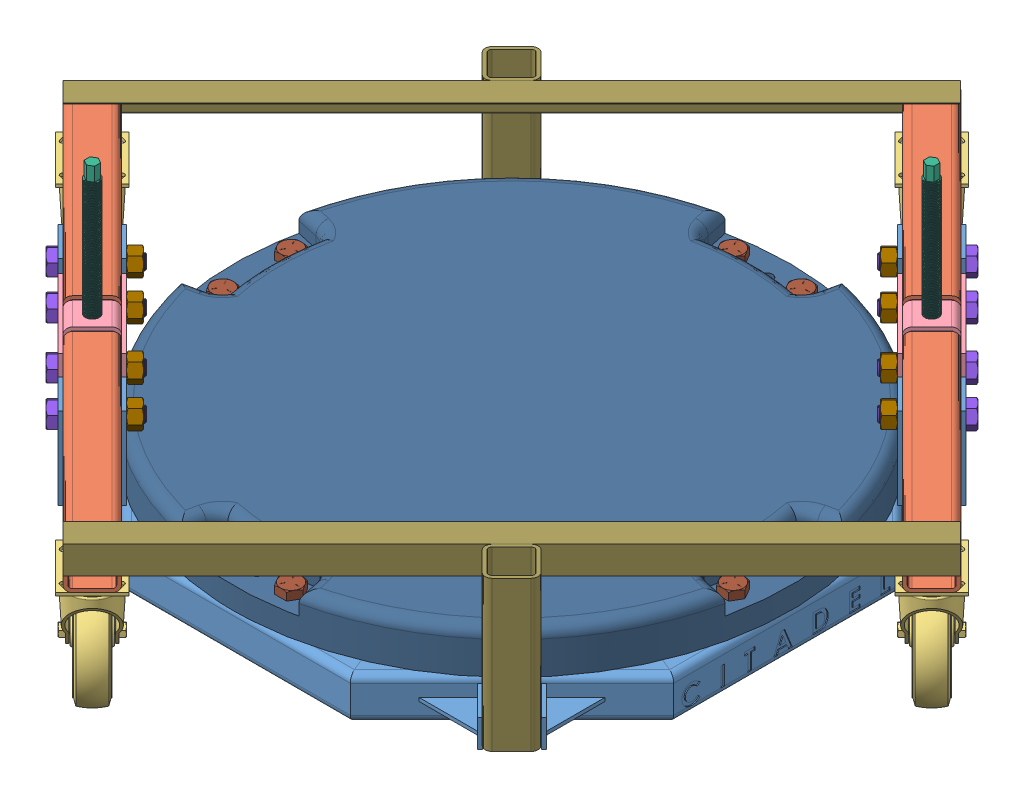
SolidWorks assembly Hex Base Tubing Assembly2 screw, configuration Default. Lengths in mm.
Overall size (1664.24 559.66 1664.24).
54 component instances, 12 part files, 81 mates.
Components (placement in the parent):
- Hex Base Box Tubing-1: Hex Base Box Tubing [Default<As Machined>] at (554.5207 455.268 811.2927) x (0 0 -1) z (0 1 0) size (1171.84 1171.84 285.75)
- Tube Arm-1: Tube Arm [Default<As Machined>] at (910.3441 671.4952 398.9153) x (-0.707105 -0.002496 -0.707105) z (-0.707107 0 0.707107) size (476.53 76.2 76.2)
- Tube Arm-2: Tube Arm [Default<As Machined>] at (966.8981 671.4952 455.4693) x (0.707105 -0.002496 0.707105) z (-0.707107 0 0.707107) size (476.53 76.2 76.2)
- Tube Arm-3: Tube Arm [Default<As Machined>] at (142.1433 671.4952 1167.1161) x (-0.707105 -0.002496 -0.707105) z (-0.707107 0 0.707107) size (476.53 76.2 76.2)
- Tube Arm-4: Tube Arm [Default<As Machined>] at (198.6973 671.4952 1223.6701) x (0.707105 -0.002496 0.707105) z (-0.707107 0 0.707107) size (476.53 76.2 76.2)
- 2498T660_EASY-TURN NSF-CERTIFIED CASTER-1: 2498T660_EASY-TURN NSF-CERTIFIED CASTER [2498T66] at (614.9884 632.3527 103.5596) x (-0.707105 -0.002496 -0.707105) z (0.707107 0 -0.707107) size (215.9 241.3 95.25)
- 2498T660_EASY-TURN NSF-CERTIFIED CASTER-2: 2498T660_EASY-TURN NSF-CERTIFIED CASTER [2498T66] at (1262.2538 632.3527 750.825) x (0.707105 -0.002496 0.707105) z (-0.707107 0 0.707107) size (215.9 241.3 95.25)
- 2498T660_EASY-TURN NSF-CERTIFIED CASTER-3: 2498T660_EASY-TURN NSF-CERTIFIED CASTER [2498T66] at (-153.2124 632.3527 871.7604) x (-0.707105 -0.002496 -0.707105) z (0.707107 0 -0.707107) size (215.9 241.3 95.25)
- 2498T660_EASY-TURN NSF-CERTIFIED CASTER-4: 2498T660_EASY-TURN NSF-CERTIFIED CASTER [2498T66] at (494.053 632.3527 1519.0258) x (0.707105 -0.002496 0.707105) z (-0.707107 0 0.707107) size (215.9 241.3 95.25)
- Coupler-2 Assembly-1: Coupler-2 Assembly [Default] at (973.9039 570.6335 267.0357) x (0.707107 0 0.707107) z (-0.707107 0 0.707107) size (180 101.54 88.9)
  - Center Tube Coupler-2-1: Center Tube Coupler-2 [Default<As Machined>] at (58.2991 100.7931 138.1965) size (180 76.2 88.9)
  - 94815A118_RIGHT-HAND GENERAL PURPOSE ACME HEX NUT-2: 94815A118_RIGHT-HAND GENERAL PURPOSE ACME HEX NUT [94815A118] at (88.2991 50.1915 138.1965) x (-0.537908 0 -0.843004) z (0 1 0) size (41.27 52.42 25.67)
  - 94815A118_RIGHT-HAND GENERAL PURPOSE ACME HEX NUT-3: 94815A118_RIGHT-HAND GENERAL PURPOSE ACME HEX NUT [94815A118] at (88.2991 120.0415 138.1965) x (1 0 0) z (0 1 0) size (41.27 52.42 25.67)
- 98935A754_ASTM A108 STEEL ACME LEAD SCREW-18 inch-1: 98935A754_ASTM A108 STEEL ACME LEAD SCREW-18 inch [98935A754] at (938.6211 721.968 427.1923) x (1 0 0) z (0 1 0) size (29.33 26.07 459.74)
- Coupler-2 Assembly-2: Coupler-2 Assembly [Default] at (205.7031 570.6335 1035.2365) x (0.707107 0 0.707107) z (-0.707107 0 0.707107) size (180 101.54 88.9)
  - Center Tube Coupler-2-1: Center Tube Coupler-2 [Default<As Machined>] at (58.2991 100.7931 138.1965) size (180 76.2 88.9)
  - 94815A118_RIGHT-HAND GENERAL PURPOSE ACME HEX NUT-2: 94815A118_RIGHT-HAND GENERAL PURPOSE ACME HEX NUT [94815A118] at (88.2991 50.1915 138.1965) x (-0.537908 0 -0.843004) z (0 1 0) size (41.27 52.42 25.67)
  - 94815A118_RIGHT-HAND GENERAL PURPOSE ACME HEX NUT-3: 94815A118_RIGHT-HAND GENERAL PURPOSE ACME HEX NUT [94815A118] at (88.2991 120.0415 138.1965) x (1 0 0) z (0 1 0) size (41.27 52.42 25.67)
- 98935A754_ASTM A108 STEEL ACME LEAD SCREW-18 inch-2: 98935A754_ASTM A108 STEEL ACME LEAD SCREW-18 inch [98935A754] at (170.4203 721.968 1195.3931) x (1 0 0) z (0 1 0) size (29.33 26.07 459.74)
- Weld in Bung1-8-1: Weld in Bung1-8 [95462A548] at (617.0207 455.268 344.2927) x (-0.837169 0 -0.546944) z (0 1 0) size (31.75 31.75 92.63)
- Weld in Bung1-8-2: Weld in Bung1-8 [95462A548] at (492.0207 455.268 344.2927) x (-0.837169 0 -0.546944) z (0 1 0) size (31.75 31.75 92.63)
- Weld in Bung1-8-3: Weld in Bung1-8 [95462A548] at (617.0207 455.268 1278.2927) x (-0.837169 0 -0.546944) z (0 1 0) size (31.75 31.75 92.63)
- Weld in Bung1-8-4: Weld in Bung1-8 [95462A548] at (87.5207 455.268 748.7927) x (-0.837169 0 -0.546944) z (0 1 0) size (31.75 31.75 92.63)
- Weld in Bung1-8-5: Weld in Bung1-8 [95462A548] at (1021.5207 455.268 873.7927) x (-0.837169 0 -0.546944) z (0 1 0) size (31.75 31.75 92.63)
- Weld in Bung1-8-6: Weld in Bung1-8 [95462A548] at (87.5207 455.268 873.7927) x (-0.837169 0 -0.546944) z (0 1 0) size (31.75 31.75 92.63)
- Weld in Bung1-8-7: Weld in Bung1-8 [95462A548] at (1021.5207 455.268 748.7927) x (-0.837169 0 -0.546944) z (0 1 0) size (31.75 31.75 92.63)
- Weld in Bung1-8-8: Weld in Bung1-8 [95462A548] at (492.0207 455.268 1278.2927) x (-0.837169 0 -0.546944) z (0 1 0) size (31.75 31.75 92.63)
- 91247A922_MEDIUM-STRG GRADE 5 ZINC-PLTD STL CAP SCREW-1: 91247A922_MEDIUM-STRG GRADE 5 ZINC-PLTD STL CAP SCREW [91247A922] at (221.6579 671.4266 1239.6149) x (0.707107 0 -0.707107) z (0.707107 0 0.707107) size (131 43.99 38.1)
- 91247A922_MEDIUM-STRG GRADE 5 ZINC-PLTD STL CAP SCREW-2: 91247A922_MEDIUM-STRG GRADE 5 ZINC-PLTD STL CAP SCREW [91247A922] at (126.1985 671.4266 1144.1555) x (0.707107 0 -0.707107) z (0.707107 0 0.707107) size (131 43.99 38.1)
- 91247A922_MEDIUM-STRG GRADE 5 ZINC-PLTD STL CAP SCREW-3: 91247A922_MEDIUM-STRG GRADE 5 ZINC-PLTD STL CAP SCREW [91247A922] at (52.9286 671.168 1070.8856) x (0.707107 0 -0.707107) z (0.707107 0 0.707107) size (131 43.99 38.1)
- 91247A922_MEDIUM-STRG GRADE 5 ZINC-PLTD STL CAP SCREW-4: 91247A922_MEDIUM-STRG GRADE 5 ZINC-PLTD STL CAP SCREW [91247A922] at (294.9278 671.168 1312.8848) x (0.707107 0 -0.707107) z (0.707107 0 0.707107) size (131 43.99 38.1)
- 91247A922_MEDIUM-STRG GRADE 5 ZINC-PLTD STL CAP SCREW-5: 91247A922_MEDIUM-STRG GRADE 5 ZINC-PLTD STL CAP SCREW [91247A922] at (887.3835 671.4266 382.9705) x (-0.707107 0 0.707107) z (-0.643511 -0.414472 -0.643511) size (131 43.99 38.1)
- 91247A922_MEDIUM-STRG GRADE 5 ZINC-PLTD STL CAP SCREW-6: 91247A922_MEDIUM-STRG GRADE 5 ZINC-PLTD STL CAP SCREW [91247A922] at (1056.1128 671.168 551.6998) x (-0.707107 0 0.707107) z (-0.643511 -0.414472 -0.643511) size (131 43.99 38.1)
- 91247A922_MEDIUM-STRG GRADE 5 ZINC-PLTD STL CAP SCREW-7: 91247A922_MEDIUM-STRG GRADE 5 ZINC-PLTD STL CAP SCREW [91247A922] at (814.1136 671.168 309.7006) x (-0.707107 0 0.707107) z (-0.643511 -0.414472 -0.643511) size (131 43.99 38.1)
- 91247A922_MEDIUM-STRG GRADE 5 ZINC-PLTD STL CAP SCREW-8: 91247A922_MEDIUM-STRG GRADE 5 ZINC-PLTD STL CAP SCREW [91247A922] at (982.8429 671.4266 478.4299) x (-0.707107 0 0.707107) z (-0.643511 -0.414472 -0.643511) size (131 43.99 38.1)
- 95462A548_GRADE 5 STEEL HEX NUT-1: 95462A548_GRADE 5 STEEL HEX NUT [95462A548] at (778.4732 671.168 345.341) x (0.707107 0 0.707107) z (-0.707107 0 0.707107) size (38.1 43.99 27.38)
- 95462A548_GRADE 5 STEEL HEX NUT-2: 95462A548_GRADE 5 STEEL HEX NUT [95462A548] at (947.2025 671.4266 514.0703) x (0.707107 0 0.707107) z (-0.707107 0 0.707107) size (38.1 43.99 27.38)
- 95462A548_GRADE 5 STEEL HEX NUT-3: 95462A548_GRADE 5 STEEL HEX NUT [95462A548] at (1020.4724 671.168 587.3402) x (0.707107 0 0.707107) z (-0.707107 0 0.707107) size (38.1 43.99 27.38)
- 95462A548_GRADE 5 STEEL HEX NUT-4: 95462A548_GRADE 5 STEEL HEX NUT [95462A548] at (851.7431 671.4266 418.6109) x (0.707107 0 0.707107) z (-0.707107 0 0.707107) size (38.1 43.99 27.38)
- 95462A548_GRADE 5 STEEL HEX NUT-5: 95462A548_GRADE 5 STEEL HEX NUT [95462A548] at (88.569 671.168 1035.2452) x (-0.643511 -0.414472 -0.643511) z (0.707107 0 -0.707107) size (38.1 43.99 27.38)
- 95462A548_GRADE 5 STEEL HEX NUT-6: 95462A548_GRADE 5 STEEL HEX NUT [95462A548] at (257.2983 671.4266 1203.9745) x (-0.643511 -0.414472 -0.643511) z (0.707107 0 -0.707107) size (38.1 43.99 27.38)
- 95462A548_GRADE 5 STEEL HEX NUT-7: 95462A548_GRADE 5 STEEL HEX NUT [95462A548] at (161.8389 671.4266 1108.5151) x (-0.643511 -0.414472 -0.643511) z (0.707107 0 -0.707107) size (38.1 43.99 27.38)
- 95462A548_GRADE 5 STEEL HEX NUT-8: 95462A548_GRADE 5 STEEL HEX NUT [95462A548] at (330.5682 671.168 1277.2444) x (-0.643511 -0.414472 -0.643511) z (0.707107 0 -0.707107) size (38.1 43.99 27.38)
- Kuka Base-1: Kuka Base [Default] at (554.5207 493.368 811.2927) x (0 0 1) z (0 1 0) size (1020 1020 81.77)
- 92865A914_MEDIUM-STRG GRADE 5 ZINC-PLTD STL CAP SCREW-3: 92865A914_MEDIUM-STRG GRADE 5 ZINC-PLTD STL CAP SCREW [92865A914] at (492.0207 509.357 1278.2927) x (0 -1 0) z (0 0 1) size (80.56 43.99 38.1)
- 92865A914_MEDIUM-STRG GRADE 5 ZINC-PLTD STL CAP SCREW-4: 92865A914_MEDIUM-STRG GRADE 5 ZINC-PLTD STL CAP SCREW [92865A914] at (87.5207 509.357 873.7927) x (0 -1 0) z (0 0 1) size (80.56 43.99 38.1)
- 92865A914_MEDIUM-STRG GRADE 5 ZINC-PLTD STL CAP SCREW-5: 92865A914_MEDIUM-STRG GRADE 5 ZINC-PLTD STL CAP SCREW [92865A914] at (492.0207 509.357 344.2927) x (0 -1 0) z (0 0 1) size (80.56 43.99 38.1)
- 92865A914_MEDIUM-STRG GRADE 5 ZINC-PLTD STL CAP SCREW-6: 92865A914_MEDIUM-STRG GRADE 5 ZINC-PLTD STL CAP SCREW [92865A914] at (617.0207 509.357 1278.2927) x (0 -1 0) z (0 0 1) size (80.56 43.99 38.1)
- 92865A914_MEDIUM-STRG GRADE 5 ZINC-PLTD STL CAP SCREW-7: 92865A914_MEDIUM-STRG GRADE 5 ZINC-PLTD STL CAP SCREW [92865A914] at (617.0207 509.357 344.2927) x (0 -1 0) z (0 0 1) size (80.56 43.99 38.1)
- 92865A914_MEDIUM-STRG GRADE 5 ZINC-PLTD STL CAP SCREW-8: 92865A914_MEDIUM-STRG GRADE 5 ZINC-PLTD STL CAP SCREW [92865A914] at (1021.5207 509.357 873.7927) x (0 -1 0) z (0 0 1) size (80.56 43.99 38.1)
- 92865A914_MEDIUM-STRG GRADE 5 ZINC-PLTD STL CAP SCREW-9: 92865A914_MEDIUM-STRG GRADE 5 ZINC-PLTD STL CAP SCREW [92865A914] at (87.5207 509.357 748.7927) x (0 -1 0) z (0 0 1) size (80.56 43.99 38.1)
- 92865A914_MEDIUM-STRG GRADE 5 ZINC-PLTD STL CAP SCREW-10: 92865A914_MEDIUM-STRG GRADE 5 ZINC-PLTD STL CAP SCREW [92865A914] at (1021.5207 509.357 748.7927) x (0 -1 0) z (0 0 1) size (80.56 43.99 38.1)
- Angle Cross Brace-1: Angle Cross Brace [Default<As Machined>] at (-224.0719 711.5729 854.7825) x (0.707107 0 -0.707107) z (0.001765 -0.999997 0.001765) size (1161.6 127 275)
- Angle Cross Brace-2: Angle Cross Brace [Default<As Machined>] at (1332.4062 711.5729 768.51) x (-0.707107 0 0.707107) z (-0.001765 -0.999997 -0.001765) size (1161.6 127 275)
Mates (geometry in assembly coordinates):
- Coincident1: coincident: cylinder of Hex Base Box Tubing-1 through (849.0524 671.168 274.7618) axis (-0.707107 0 0.707107) radius 12.7; circle of Tube Arm-1
- Coincident2: coincident: plane of Hex Base Box Tubing-1 through (965.5619 455.268 400.2515) normal (-0.707107 0 0.707107); plane of Tube Arm-1 through (600.2835 695.7059 34.9732) normal (0.707107 0 -0.707107)
- Concentric1: concentric: cylinder of Hex Base Box Tubing-1 through (1091.0516 671.168 516.761) axis (-0.707107 0 0.707107) radius 12.7; cylinder of Tube Arm-2 through (1086.5615 671.168 521.2511) axis (-0.707107 0 0.707107) radius 12.7
- Coincident3: coincident: plane of Hex Base Box Tubing-1 through (965.5619 455.268 400.2515) normal (-0.707107 0 0.707107); plane of Tube Arm-2 through (1330.7506 644.9061 765.4402) normal (0.707107 0 -0.707107)
- Concentric6: concentric: cylinder of Hex Base Box Tubing-1 through (322.8508 671.168 1284.9618) axis (-0.707107 0 0.707107) radius 12.7; cylinder of Tube Arm-4 through (318.3607 671.168 1289.4519) axis (-0.707107 0 0.707107) radius 12.7
- Coincident7: coincident: plane of Hex Base Box Tubing-1 through (143.4795 455.268 1222.3339) normal (0.707107 0 -0.707107); plane of Tube Arm-4 through (508.7579 695.7059 1587.6122) normal (-0.707107 0 0.707107)
- Concentric7: concentric: cylinder of Hex Base Box Tubing-1 through (17.9898 671.168 1105.8244) axis (0.707107 0 -0.707107) radius 12.7; cylinder of Tube Arm-3 through (76.3615 671.168 1047.4527) axis (-0.707107 0 0.707107) radius 12.7
- Coincident8: coincident: plane of Hex Base Box Tubing-1 through (197.3611 455.268 1168.4523) normal (-0.707107 0 0.707107); plane of Tube Arm-3 through (-167.9173 695.7059 803.174) normal (0.707107 0 -0.707107)
- Coincident14: coincident: plane of Tube Arm-1 through (555.4943 632.2061 79.9865) normal (0.001765 -0.999997 0.001765); plane of 2498T660_EASY-TURN NSF-CERTIFIED CASTER-1 through (690.1979 632.4993 111.4172) normal (-0.001765 0.999997 -0.001765)
- Coincident15: coincident: plane of Tube Arm-1 through (555.4719 644.9061 79.9641) normal (-0.707105 -0.002496 -0.707105); plane of 2498T660_EASY-TURN NSF-CERTIFIED CASTER-1 through (539.7887 626.6499 95.7118) normal (-0.707105 -0.002496 -0.707105)
- Distance1: distance = 9.525 mm: plane of 2498T660_EASY-TURN NSF-CERTIFIED CASTER-1 through (690.2077 626.9431 111.427) normal (0.707107 0 -0.707107); plane of Tube Arm-1 through (600.2835 695.7059 34.9732) normal (0.707107 0 -0.707107)
- Coincident18: coincident: plane of Tube Arm-2 through (1321.7479 632.2061 774.3981) normal (-0.001765 -0.999997 -0.001765); plane of 2498T660_EASY-TURN NSF-CERTIFIED CASTER-2 through (1187.0443 632.4993 742.9674) normal (0.001765 0.999997 0.001765)
- Coincident20: coincident: plane of Tube Arm-2 through (1285.9389 695.7059 810.4311) normal (0.707105 -0.002496 0.707105); plane of 2498T660_EASY-TURN NSF-CERTIFIED CASTER-2 through (1337.4536 626.6499 758.6728) normal (0.707105 -0.002496 0.707105)
- Distance2: distance = 9.525 mm: plane of Tube Arm-2 through (1330.7506 644.9061 765.4402) normal (0.707107 0 -0.707107); plane of 2498T660_EASY-TURN NSF-CERTIFIED CASTER-2 through (1254.3864 626.9431 675.6057) normal (0.707107 0 -0.707107)
- Coincident22: coincident: plane of Tube Arm-3 through (-212.7065 632.2061 848.1873) normal (0.001765 -0.999997 0.001765); plane of 2498T660_EASY-TURN NSF-CERTIFIED CASTER-3 through (-78.0029 632.4993 879.618) normal (-0.001765 0.999997 -0.001765)
- Coincident23: coincident: plane of Tube Arm-3 through (-212.7289 644.9061 848.1649) normal (-0.707105 -0.002496 -0.707105); plane of 2498T660_EASY-TURN NSF-CERTIFIED CASTER-3 through (-228.4121 626.6499 863.9126) normal (-0.707105 -0.002496 -0.707105)
- Distance3: distance = 9.525 mm: plane of Tube Arm-3 through (-167.9173 695.7059 803.174) normal (0.707107 0 -0.707107); plane of 2498T660_EASY-TURN NSF-CERTIFIED CASTER-3 through (-77.9931 626.9431 879.6278) normal (0.707107 0 -0.707107)
- Coincident25: coincident: plane of Tube Arm-4 through (553.5471 632.2061 1542.5989) normal (-0.001765 -0.999997 -0.001765); plane of 2498T660_EASY-TURN NSF-CERTIFIED CASTER-4 through (418.8435 632.4993 1511.1682) normal (0.001765 0.999997 0.001765)
- Coincident26: coincident: plane of Tube Arm-4 through (517.7381 695.7059 1578.632) normal (0.707105 -0.002496 0.707105); plane of 2498T660_EASY-TURN NSF-CERTIFIED CASTER-4 through (569.2527 626.6499 1526.8736) normal (0.707105 -0.002496 0.707105)
- Distance4: distance = 9.525 mm: plane of Tube Arm-4 through (562.5498 644.9061 1533.641) normal (0.707107 0 -0.707107); plane of 2498T660_EASY-TURN NSF-CERTIFIED CASTER-4 through (486.1856 626.9431 1443.8065) normal (0.707107 0 -0.707107)
- Slot1: slot: cylinder of Tube Arm-1 through (911.7231 671.405 346.4127) axis (-0.707107 0 0.707107) radius 12.7; cylinder of Coupler-2 Assembly-1/Center Tube Coupler-2-1 through (922.3223 671.4266 348.0317) axis (-0.707107 0 0.707107) radius 12.7; cylinder of Tube Arm-1 through (924.1681 671.4489 358.8578) axis (-0.707107 0 0.707107) radius 12.7
- Slot2: slot: cylinder of Tube Arm-2 through (1019.4007 671.405 454.0903) axis (-0.707107 0 0.707107) radius 12.7; cylinder of Coupler-2 Assembly-1/Center Tube Coupler-2-1 through (1017.7817 671.4266 443.4911) axis (-0.707107 0 0.707107) radius 12.7; cylinder of Tube Arm-2 through (1006.9556 671.4489 441.6453) axis (-0.707107 0 0.707107) radius 12.7
- Coincident70: coincident: plane of Tube Arm-2 through (1330.7506 644.9061 765.4402) normal (0.707107 0 -0.707107); plane of Coupler-2 Assembly-1/Center Tube Coupler-2-1 through (944.3487 671.4266 379.0383) normal (-0.707107 0 0.707107)
- Concentric8: concentric: circle of Coupler-2 Assembly-1/Center Tube Coupler-2-1; circle of 98935A754_ASTM A108 STEEL ACME LEAD SCREW-18 inch-1
- Concentric9: concentric: circle of Hex Base Box Tubing-1; circle of 98935A754_ASTM A108 STEEL ACME LEAD SCREW-18 inch-1
- Coincident71: coincident: plane of Hex Base Box Tubing-1 through (1050.6405 493.368 503.2906) normal (0 1 0); plane of 98935A754_ASTM A108 STEEL ACME LEAD SCREW-18 inch-1 through (938.6211 493.368 427.1923) normal (0 -1 0)
- Slot3: slot: cylinder of Tube Arm-3 through (143.5223 671.405 1114.6135) axis (-0.707107 0 0.707107) radius 12.7; cylinder of Coupler-2 Assembly-2/Center Tube Coupler-2-1 through (91.2597 671.4266 1179.0943) axis (0.707107 0 -0.707107) radius 12.7; cylinder of Tube Arm-3 through (155.9673 671.4489 1127.0586) axis (-0.707107 0 0.707107) radius 12.7
- Slot4: slot: cylinder of Tube Arm-4 through (251.1999 671.405 1222.2911) axis (-0.707107 0 0.707107) radius 12.7; cylinder of Coupler-2 Assembly-2/Center Tube Coupler-2-1 through (186.7191 671.4266 1274.5537) axis (0.707107 0 -0.707107) radius 12.7; cylinder of Tube Arm-4 through (238.7548 671.4489 1209.8461) axis (-0.707107 0 0.707107) radius 12.7
- Coincident72: coincident: plane of Tube Arm-4 through (508.7579 695.7059 1587.6122) normal (-0.707107 0 0.707107); plane of Coupler-2 Assembly-2/Center Tube Coupler-2-1 through (122.2663 671.4266 1201.1207) normal (0.707107 0 -0.707107)
- Concentric10: concentric: circle of Coupler-2 Assembly-2/Center Tube Coupler-2-1; circle of 98935A754_ASTM A108 STEEL ACME LEAD SCREW-18 inch-2
- Concentric11: concentric: circle of Hex Base Box Tubing-1; circle of 98935A754_ASTM A108 STEEL ACME LEAD SCREW-18 inch-2
- Coincident73: coincident: plane of Hex Base Box Tubing-1 through (58.401 493.368 1119.2948) normal (0 1 0); plane of 98935A754_ASTM A108 STEEL ACME LEAD SCREW-18 inch-2 through (170.4203 493.368 1195.3931) normal (0 -1 0)
- Coincident74: coincident: circle of Hex Base Box Tubing-1; circle of Weld in Bung1-8-1
- Coincident75: coincident: circle of Hex Base Box Tubing-1; circle of Weld in Bung1-8-2
- Coincident76: coincident: circle of Hex Base Box Tubing-1; circle of Weld in Bung1-8-7
- Coincident77: coincident: circle of Hex Base Box Tubing-1; circle of Weld in Bung1-8-5
- Coincident78: coincident: circle of Hex Base Box Tubing-1; circle of Weld in Bung1-8-4
- Coincident79: coincident: circle of Hex Base Box Tubing-1; circle of Weld in Bung1-8-6
- Coincident80: coincident: circle of Hex Base Box Tubing-1; circle of Weld in Bung1-8-3
- Coincident81: coincident: circle of Hex Base Box Tubing-1; circle of Weld in Bung1-8-8
- Coincident82: coincident: circle of Coupler-2 Assembly-2/Center Tube Coupler-2-1; circle of 91247A922_MEDIUM-STRG GRADE 5 ZINC-PLTD STL CAP SCREW-1
- Coincident83: coincident: circle of Hex Base Box Tubing-1; circle of 91247A922_MEDIUM-STRG GRADE 5 ZINC-PLTD STL CAP SCREW-4
- Coincident84: coincident: circle of Coupler-2 Assembly-2/Center Tube Coupler-2-1; circle of 91247A922_MEDIUM-STRG GRADE 5 ZINC-PLTD STL CAP SCREW-2
- Coincident85: coincident: circle of Hex Base Box Tubing-1; circle of 91247A922_MEDIUM-STRG GRADE 5 ZINC-PLTD STL CAP SCREW-3
- Coincident86: coincident: circle of Hex Base Box Tubing-1; circle of 91247A922_MEDIUM-STRG GRADE 5 ZINC-PLTD STL CAP SCREW-7
- Coincident87: coincident: circle of Coupler-2 Assembly-1/Center Tube Coupler-2-1; circle of 91247A922_MEDIUM-STRG GRADE 5 ZINC-PLTD STL CAP SCREW-5
- Coincident88: coincident: circle of Coupler-2 Assembly-1/Center Tube Coupler-2-1; circle of 91247A922_MEDIUM-STRG GRADE 5 ZINC-PLTD STL CAP SCREW-8
- Coincident89: coincident: circle of Hex Base Box Tubing-1; circle of 91247A922_MEDIUM-STRG GRADE 5 ZINC-PLTD STL CAP SCREW-6
- Coincident91: coincident: circle of Hex Base Box Tubing-1; circle of 95462A548_GRADE 5 STEEL HEX NUT-1
- Coincident92: coincident: circle of Coupler-2 Assembly-1/Center Tube Coupler-2-1; circle of 95462A548_GRADE 5 STEEL HEX NUT-4
- Coincident93: coincident: circle of Coupler-2 Assembly-1/Center Tube Coupler-2-1; circle of 95462A548_GRADE 5 STEEL HEX NUT-2
- Coincident94: coincident: circle of Hex Base Box Tubing-1; circle of 95462A548_GRADE 5 STEEL HEX NUT-3
- Coincident95: coincident: circle of Hex Base Box Tubing-1; circle of 95462A548_GRADE 5 STEEL HEX NUT-5
- Coincident96: coincident: circle of Coupler-2 Assembly-2/Center Tube Coupler-2-1; circle of 95462A548_GRADE 5 STEEL HEX NUT-7
- Coincident97: coincident: circle of Coupler-2 Assembly-2/Center Tube Coupler-2-1; circle of 95462A548_GRADE 5 STEEL HEX NUT-6
- Coincident98: coincident: circle of Hex Base Box Tubing-1; circle of 95462A548_GRADE 5 STEEL HEX NUT-8
- Concentric12: concentric: circle of Hex Base Box Tubing-1; circle of Kuka Base-1
- Coincident100: coincident: plane of Hex Base Box Tubing-1 through (747.9584 493.368 1252.8927) normal (0 1 0); plane of Kuka Base-1 through (554.5207 493.368 811.2927) normal (0 -1 0)
- Concentric13: concentric: circle of Weld in Bung1-8-5; circle of Kuka Base-1
- Concentric14: concentric: circle of Kuka Base-1; circle of 92865A914_MEDIUM-STRG GRADE 5 ZINC-PLTD STL CAP SCREW-3
- Coincident101: coincident: plane of Kuka Base-1 through (554.5207 533.368 811.2927) normal (0 1 0); plane of 92865A914_MEDIUM-STRG GRADE 5 ZINC-PLTD STL CAP SCREW-3 through (503.0192 533.368 1297.3427) normal (0 -1 0)
- Concentric15: concentric: circle of Kuka Base-1; circle of 92865A914_MEDIUM-STRG GRADE 5 ZINC-PLTD STL CAP SCREW-6
- Coincident102: coincident: plane of Kuka Base-1 through (554.5207 533.368 811.2927) normal (0 1 0); plane of 92865A914_MEDIUM-STRG GRADE 5 ZINC-PLTD STL CAP SCREW-6 through (628.0192 533.368 1297.3427) normal (0 -1 0)
- Concentric16: concentric: circle of Kuka Base-1; circle of 92865A914_MEDIUM-STRG GRADE 5 ZINC-PLTD STL CAP SCREW-9
- Coincident103: coincident: plane of Kuka Base-1 through (554.5207 533.368 811.2927) normal (0 1 0); plane of 92865A914_MEDIUM-STRG GRADE 5 ZINC-PLTD STL CAP SCREW-9 through (98.5192 533.368 767.8427) normal (0 -1 0)
- Concentric17: concentric: circle of Kuka Base-1; circle of 92865A914_MEDIUM-STRG GRADE 5 ZINC-PLTD STL CAP SCREW-4
- Coincident104: coincident: plane of Kuka Base-1 through (554.5207 533.368 811.2927) normal (0 1 0); plane of 92865A914_MEDIUM-STRG GRADE 5 ZINC-PLTD STL CAP SCREW-4 through (98.5192 533.368 892.8427) normal (0 -1 0)
- Concentric18: concentric: circle of Kuka Base-1; circle of 92865A914_MEDIUM-STRG GRADE 5 ZINC-PLTD STL CAP SCREW-8
- Coincident105: coincident: plane of Kuka Base-1 through (554.5207 533.368 811.2927) normal (0 1 0); plane of 92865A914_MEDIUM-STRG GRADE 5 ZINC-PLTD STL CAP SCREW-8 through (1032.5192 533.368 892.8427) normal (0 -1 0)
- Concentric19: concentric: circle of Kuka Base-1; circle of 92865A914_MEDIUM-STRG GRADE 5 ZINC-PLTD STL CAP SCREW-10
- Coincident106: coincident: plane of Kuka Base-1 through (554.5207 533.368 811.2927) normal (0 1 0); plane of 92865A914_MEDIUM-STRG GRADE 5 ZINC-PLTD STL CAP SCREW-10 through (1032.5192 533.368 767.8427) normal (0 -1 0)
- Concentric20: concentric: circle of Kuka Base-1; circle of 92865A914_MEDIUM-STRG GRADE 5 ZINC-PLTD STL CAP SCREW-5
- Coincident107: coincident: plane of Kuka Base-1 through (554.5207 533.368 811.2927) normal (0 1 0); plane of 92865A914_MEDIUM-STRG GRADE 5 ZINC-PLTD STL CAP SCREW-5 through (503.0192 533.368 363.3427) normal (0 -1 0)
- Concentric21: concentric: circle of Kuka Base-1; circle of 92865A914_MEDIUM-STRG GRADE 5 ZINC-PLTD STL CAP SCREW-7
- Coincident108: coincident: plane of Kuka Base-1 through (554.5207 533.368 811.2927) normal (0 1 0); plane of 92865A914_MEDIUM-STRG GRADE 5 ZINC-PLTD STL CAP SCREW-7 through (628.0192 533.368 363.3427) normal (0 -1 0)
- Coincident109: coincident: plane of Tube Arm-3 through (-176.9199 708.4059 812.1318) normal (-0.001765 0.999997 -0.001765); plane of Angle Cross Brace-1 through (602.9216 708.4178 39.0255) normal (0.001765 -0.999997 0.001765)
- Coincident110: coincident: plane of Tube Arm-3 through (-221.7092 644.9061 857.1452) normal (-0.707107 0 0.707107); plane of Angle Cross Brace-1 through (-223.9842 663.943 854.8701) normal (-0.707107 0 0.707107)
- Coincident111: coincident: plane of Tube Arm-3 through (-212.7289 644.9061 848.1649) normal (-0.707105 -0.002496 -0.707105); plane of Angle Cross Brace-1 through (599.6325 663.9509 35.7363) normal (0.707105 0.002496 0.707105)
- Coincident113: coincident: plane of Tube Arm-2 through (1285.9614 708.4059 810.4536) normal (0.001765 0.999997 0.001765); plane of Angle Cross Brace-2 through (505.4127 708.4178 1584.267) normal (-0.001765 -0.999997 -0.001765)
- Coincident114: coincident: plane of Tube Arm-4 through (508.7579 695.7059 1587.6122) normal (-0.707107 0 0.707107); plane of Angle Cross Brace-2 through (510.9433 663.943 1589.7976) normal (-0.707107 0 0.707107)
- Coincident115: coincident: plane of Tube Arm-4 through (517.7381 695.7059 1578.632) normal (0.707105 -0.002496 0.707105); plane of Angle Cross Brace-2 through (508.7018 663.9509 1587.5562) normal (-0.707105 0.002496 -0.707105)
